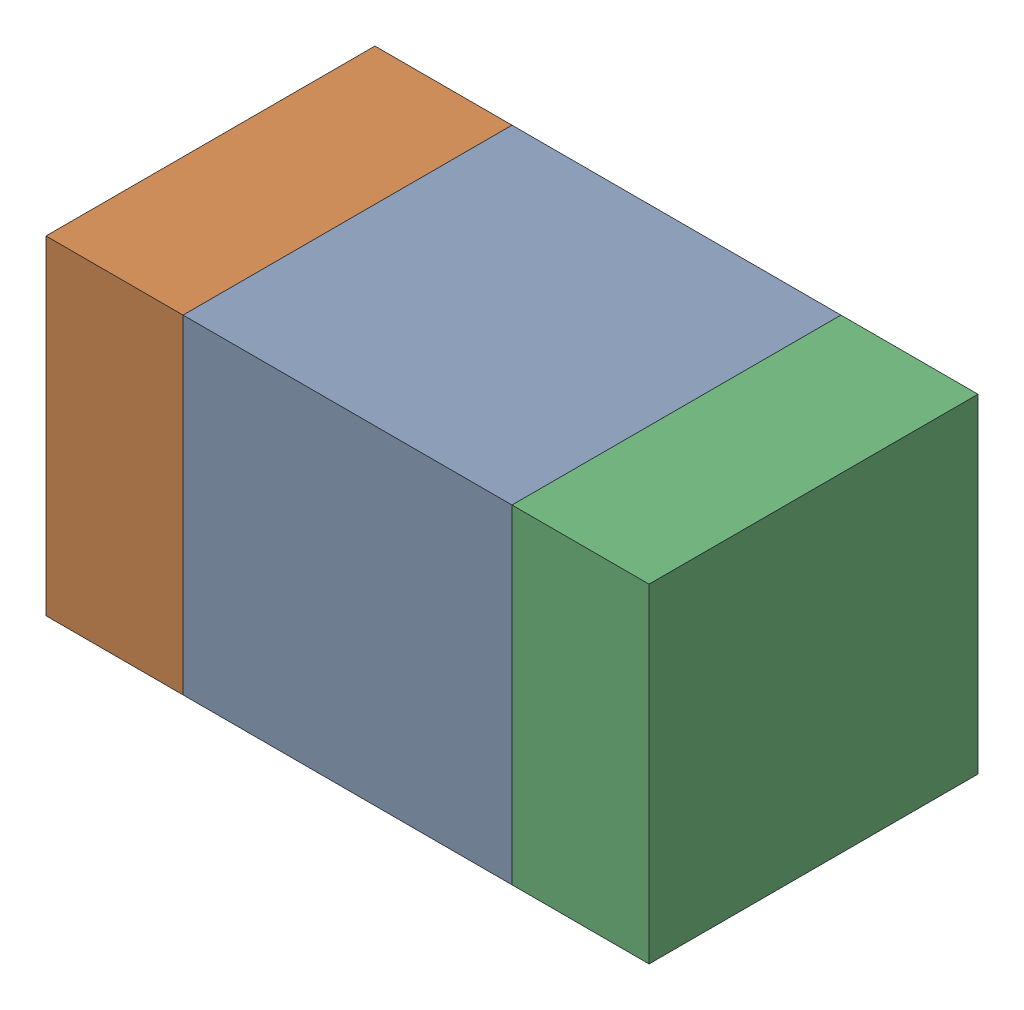
SolidWorks assembly C325_1PCB, configuration Default. Lengths in mm.
Overall size (1.1 0.6 0.6).
6 component instances, 2 part files, 0 mates.
Components (placement in the parent):
- 761606048-1: 761606048 [Default] at (135.675 116 -2.2638) size (0.6 0.6 0.6)
  - Extruded_9-1: Extruded_9 [Default] at origin size (0.6 0.6 0.6)
- 854785160-1: 854785160 [Default] at (135.25 116 -2.2638) size (0.25 0.6 0.6)
  - Extruded_19-1: Extruded_19 [Default] at origin size (0.25 0.6 0.6)
- 854785160-2: 854785160 [Default] at (136.1 116 -2.2638) size (0.25 0.6 0.6)
  - Extruded_19-1: Extruded_19 [Default] at origin size (0.25 0.6 0.6)
